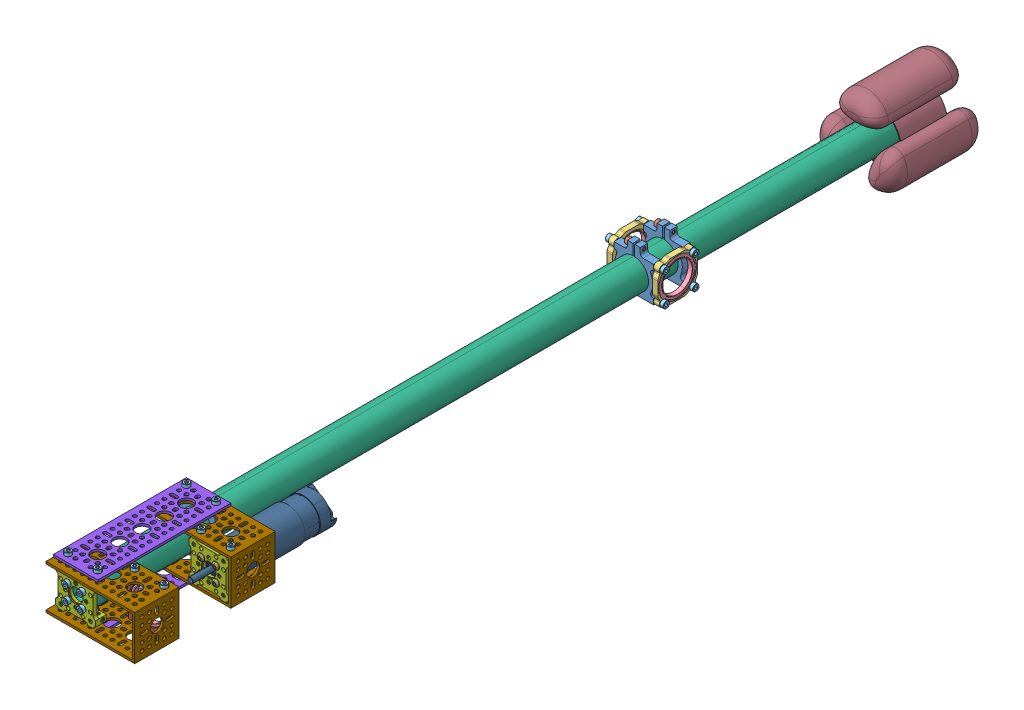
SolidWorks assembly Link2_Assembly, configuration Default. Lengths in mm.
Overall size (120.64 84 949.7).
65 component instances, 13 part files, 73 mates.
Components (placement in the parent):
- 1401-0043-0032 assembly-1: 1401-0043-0032 assembly [Default] at (-0.7931 -4.4026 -28.12) x (1 0 0) z (0 -1 0) size (43.01 8.04 47.02)
  - 1401-0043-0032 assembly.STEP-1: 1401-0043-0032 assembly.STEP [Default] at origin size (43.01 8.04 47.02)
    - 1401-0043-0032.STEP-1: 1401-0043-0032.STEP [Default] at (0.7931 12.12 -4.4026) size (43.01 8 46.5)
    - 2800-0004-0014_90128A207.STEP-1: 2800-0004-0014_90128A207.STEP [Default] at (7.7931 12.12 -28.4026) x (0 0.161804 -0.986823) z (1 0 0) size (7 7 18.01)
- 1401-0043-0032 assembly-2: 1401-0043-0032 assembly [Default] at (-0.7931 -4.4026 3.88) x (1 0 0) z (0 -1 0) size (43.01 8.04 47.02)
  - 1401-0043-0032 assembly.STEP-1: 1401-0043-0032 assembly.STEP [Default] at origin size (43.01 8.04 47.02)
    - 1401-0043-0032.STEP-1: 1401-0043-0032.STEP [Default] at (0.7931 12.12 -4.4026) size (43.01 8 46.5)
    - 2800-0004-0014_90128A207.STEP-1: 2800-0004-0014_90128A207.STEP [Default] at (7.7931 12.12 -28.4026) x (0 0.161804 -0.986823) z (1 0 0) size (7 7 18.01)
- 1603-0032-0032 assembly-1: 1603-0032-0032 assembly [Default] at (9.9811 31.4475 6.7305) x (0 1 0) z (0 0 -1) size (55.53 6 55.53)
  - 1603-0032-0032 assembly.STEP-1: 1603-0032-0032 assembly.STEP [Default] at origin size (55.53 6 55.53)
    - 1603-0032-0032.STEP-1: 1603-0032-0032.STEP [Default] at (-31.4475 11.5189 6.7305) size (43 6 43)
    - 1601-0039-00032.STEP-1: 1601-0039-00032.STEP [Default] at (-31.4475 15.0189 6.7305) x (0.473716 0 0.880678) z (-0.880678 0 0.473716) size (41 5 41)
- 1603-0032-0032 assembly-3: 1603-0032-0032 assembly [Default] at (-9.9811 -31.4475 6.7305) x (0 -1 0) z (0 0 -1) size (55.53 6 55.53)
  - 1603-0032-0032 assembly.STEP-1: 1603-0032-0032 assembly.STEP [Default] at origin size (55.53 6 55.53)
    - 1603-0032-0032.STEP-1: 1603-0032-0032.STEP [Default] at (-31.4475 11.5189 6.7305) size (43 6 43)
    - 1601-0039-00032.STEP-1: 1601-0039-00032.STEP [Default] at (-31.4475 15.0189 6.7305) x (0.473716 0 0.880678) z (-0.880678 0 0.473716) size (41 5 41)
- 2800-0004-0010-1: 2800-0004-0010 [Default] at (17.5 16 16) x (0 0 1) z (-1 0 0) size (7 7 14.01)
- 2800-0004-0010-2: 2800-0004-0010 [Default] at (17.5 16 -16) x (0 0 1) z (-1 0 0) size (7 7 14.01)
- 2800-0004-0010-3: 2800-0004-0010 [Default] at (17.5 -16 -16) x (0 0 1) z (-1 0 0) size (7 7 14.01)
- 2800-0004-0010-4: 2800-0004-0010 [Default] at (17.5 -16 16) x (0 0 1) z (-1 0 0) size (7 7 14.01)
- 2800-0004-0010-5: 2800-0004-0010 [Default] at (-17.5 -16 16) x (0 0 1) z (1 0 0) size (7 7 14.01)
- 2800-0004-0010-6: 2800-0004-0010 [Default] at (-17.5 16 16) x (0 0 1) z (1 0 0) size (7 7 14.01)
- 2800-0004-0010-7: 2800-0004-0010 [Default] at (-17.5 16 -16) x (0 0 1) z (1 0 0) size (7 7 14.01)
- 2800-0004-0010-8: 2800-0004-0010 [Default] at (-17.5 -16 -16) x (0 0 1) z (1 0 0) size (7 7 14.01)
- 4103-0032-0912-1: 4103-0032-0912 [Default] at (0 0 -292) x (1 0 0) z (0 -1 0) size (31.95 912 31.95)
- 1201-0043-0002-1: 1201-0043-0002 [Default] at (0 0 624) x (1 0 0) z (0 1 0) size (43.01 12.01 43.01)
- 1401-0043-0032 assembly-3: 1401-0043-0032 assembly [Default] at (4.4026 -0.7931 475.88) x (0 1 0) z (1 0 0) size (43.01 8.04 47.02)
  - 1401-0043-0032 assembly.STEP-1: 1401-0043-0032 assembly.STEP [Default] at origin size (43.01 8.04 47.02)
    - 1401-0043-0032.STEP-1: 1401-0043-0032.STEP [Default] at (0.7931 12.12 -4.4026) size (43.01 8 46.5)
    - 2800-0004-0014_90128A207.STEP-1: 2800-0004-0014_90128A207.STEP [Default] at (7.7931 12.12 -28.4026) x (0 0.161804 -0.986823) z (1 0 0) size (7 7 18.01)
- 1123-0048-0144-2: 1123-0048-0144 [Default] at (-21.5 2.5 480) x (0 -1 0) z (-1 0 0) size (2.5 144 48)
- 1111-0004-0001-2: 1111-0004-0001 [Default] at (-24 -45.5 629.5) x (0 -1 0) z (0 0 1) size (48 96 48)
- 1111-0004-0001-3: 1111-0004-0001 [Default] at (-24 -45.5 525.5) x (0 -1 0) z (0 0 1) size (48 96 48)
- 2800-0004-0010-9: 2800-0004-0010 [Default] at (-8 8 614) x (0.968627 0.248521 0) z (0 0 -1) size (7 7 14.01)
- 2800-0004-0010-10: 2800-0004-0010 [Default] at (-8 -8 614) x (-0.923728 -0.383049 0) z (0 0 -1) size (7 7 14.01)
- 2800-0004-0010-11: 2800-0004-0010 [Default] at (8 8 614) x (-0.923728 -0.383049 0) z (0 0 -1) size (7 7 14.01)
- 2800-0004-0010-12: 2800-0004-0010 [Default] at (8 -8 614) x (-0.923728 -0.383049 0) z (0 0 -1) size (7 7 14.01)
- 2800-0004-0010-13: 2800-0004-0010 [Default] at (-16 16.5 616) x (0.968627 0 -0.248521) z (0 -1 0) size (7 7 14.01)
- 2800-0004-0010-14: 2800-0004-0010 [Default] at (-16 16.5 488) x (0.968627 0 -0.248521) z (0 -1 0) size (7 7 14.01)
- 2800-0004-0010-15: 2800-0004-0010 [Default] at (16 16.5 616) x (0.968627 0 -0.248521) z (0 -1 0) size (7 7 14.01)
- 2800-0004-0010-16: 2800-0004-0010 [Default] at (16 16.5 488) x (0.968627 0 -0.248521) z (0 -1 0) size (7 7 14.01)
- 2800-0004-0010-17: 2800-0004-0010 [Default] at (-16 -16.5 616) x (0.968627 0 -0.248521) z (0 1 0) size (7 7 14.01)
- 2800-0004-0010-18: 2800-0004-0010 [Default] at (16 -16.5 616) x (0.968627 0 -0.248521) z (0 1 0) size (7 7 14.01)
- 2800-0004-0010-19: 2800-0004-0010 [Default] at (-16 -16.5 488) x (0.968627 0 -0.248521) z (0 1 0) size (7 7 14.01)
- 2800-0004-0010-20: 2800-0004-0010 [Default] at (16 -16.5 488) x (0.968627 0 -0.248521) z (0 1 0) size (7 7 14.01)
- 1123-0048-0144-3: 1123-0048-0144 [Default] at (-21.5 -48 480) x (0 -1 0) z (-1 0 0) size (2.5 144 48)
- 1201-0043-0002-2: 1201-0043-0002 [Default] at (48 0 528) x (1 0 0) z (0 1 0) size (43.01 12.01 43.01)
- 5202-0002-0027 part-1: 5202-0002-0027 part [Default] at (48 0 524) size (37.5 37.5 140.7)
- 2800-0004-0010-21: 2800-0004-0010 [Default] at (64 14 520) x (0.968627 0 -0.248521) z (0 -1 0) size (7 7 14.01)
- 2800-0004-0010-22: 2800-0004-0010 [Default] at (32 14 520) x (0.968627 0 -0.248521) z (0 -1 0) size (7 7 14.01)
- 2800-0004-0010-23: 2800-0004-0010 [Default] at (32 -14 520) x (0.968627 0 -0.248521) z (0 1 0) size (7 7 14.01)
- 2800-0004-0010-24: 2800-0004-0010 [Default] at (64 -14 520) x (0.968627 0 -0.248521) z (0 1 0) size (7 7 14.01)
- 1604-0043-0032 assembly-1: 1604-0043-0032 assembly [Default] at (25.231 4.255 568.0521) x (-1 0 0) z (0 1 0) size (56.75 7 56.75)
  - 1604-0043-0032 assembly.STEP-1: 1604-0043-0032 assembly.STEP [Default] at origin size (56.75 7 56.75)
    - 1604-0043-0032.STEP-1: 1604-0043-0032.STEP [Default] at (-22.769 20.4479 -4.255) size (43 7 43.01)
    - 1601-0039-00032.STEP-1: 1601-0039-00032.STEP [Default] at (-22.769 22.9479 -4.255) x (-0.837169 0 -0.546944) z (-0.546944 0 0.837169) size (41 5 41)
- 2802-0004-0008-1: 2802-0004-0008 [Default] at (56 8 530.2) size (7.6 7.6 10.21)
- 2802-0004-0008-2: 2802-0004-0008 [Default] at (40 8 530.2) size (7.6 7.6 10.21)
- 2800-0004-0010-25: 2800-0004-0010 [Default] at (32 14 592) x (0.968627 0 -0.248521) z (0 -1 0) size (7 7 14.01)
- 2800-0004-0010-26: 2800-0004-0010 [Default] at (64 14 592) x (0.968627 0 -0.248521) z (0 -1 0) size (7 7 14.01)
- 2800-0004-0010-27: 2800-0004-0010 [Default] at (64 -14 592) x (0.968627 0 -0.248521) z (0 1 0) size (7 7 14.01)
- 2800-0004-0010-28: 2800-0004-0010 [Default] at (32 -14 592) x (0.968627 0 -0.248521) z (0 1 0) size (7 7 14.01)
- 2802-0004-0008-3: 2802-0004-0008 [Default] at (56 -8 530.2) size (7.6 7.6 10.21)
- 2802-0004-0008-4: 2802-0004-0008 [Default] at (40 -8 530.2) size (7.6 7.6 10.21)
- Counter_Weight-1: Counter_Weight [Default] at (0 0 -267) size (88.52 84 101.4)
Mates (geometry in assembly coordinates):
- Symmetric2: symmetric aligned: plane of 1401-0043-0032 assembly-1/1401-0043-0032 assembly.STEP-1/1401-0043-0032.STEP-1 through (-21.5 -21.5 -12) normal (-1 0 0); plane of 1401-0043-0032 assembly-1/1401-0043-0032 assembly.STEP-1/1401-0043-0032.STEP-1 through (21.5 -21.5 -12) normal (1 0 0)
- Symmetric1: symmetric aligned: plane of 1401-0043-0032 assembly-1/1401-0043-0032 assembly.STEP-1/1401-0043-0032.STEP-1 through (-20.5 19 -16) normal (0 1 0); plane of 1401-0043-0032 assembly-1/1401-0043-0032 assembly.STEP-1/1401-0043-0032.STEP-1 through (-20.5 -19 -16) normal (0 -1 0); plane of assembly through (0 0 0) normal (0 1 0)
- Distance1: distance = 12 mm: plane of assembly through (0 0 0) normal (0 0 1); plane of assembly; plane of 1401-0043-0032 assembly-1/1401-0043-0032 assembly.STEP-1/1401-0043-0032.STEP-1 through (0 0 -12) normal (0 0 1)
- Concentric1: concentric aligned: cylinder of 1401-0043-0032 assembly-1/1401-0043-0032 assembly.STEP-1/1401-0043-0032.STEP-1 through (0 0 -20) axis (0 0 1) radius 16; cylinder of 1401-0043-0032 assembly-2/1401-0043-0032 assembly.STEP-1/1401-0043-0032.STEP-1 through (0 0 12) axis (0 0 1) radius 16
- Distance2: distance = 12 mm: plane of assembly through (0 0 0) normal (0 0 1); plane of assembly; plane of 1401-0043-0032 assembly-2/1401-0043-0032 assembly.STEP-1/1401-0043-0032.STEP-1 through (0 0 12) normal (0 0 -1)
- Coincident6: coincident anti-aligned: plane of 1401-0043-0032 assembly-2/1401-0043-0032 assembly.STEP-1/1401-0043-0032.STEP-1 through (21.5 -21.5 20) normal (1 0 0); plane of 1603-0032-0032 assembly-1/1603-0032-0032 assembly.STEP-1/1603-0032-0032.STEP-1 through (21.5 0 0) normal (-1 0 0)
- Concentric5: concentric anti-aligned: circle of 1401-0043-0032 assembly-1/1401-0043-0032 assembly.STEP-1/1401-0043-0032.STEP-1; cylinder of 1603-0032-0032 assembly-1/1603-0032-0032 assembly.STEP-1/1603-0032-0032.STEP-1 through (24.5 16 -16) axis (1 0 0) radius 2
- Parallel1: parallel aligned: plane of 1603-0032-0032 assembly-1/1603-0032-0032 assembly.STEP-1/1603-0032-0032.STEP-1 through (85.3112 21.5 21.5) normal (0 1 0)
- Coincident11: coincident aligned: plane of 2800-0004-0010-3 through (27.5 -16 -16) normal (-1 0 0); plane of 2800-0004-0010-4 through (27.5 -16 16) normal (-1 0 0)
- Coincident12: coincident aligned: plane of 2800-0004-0010-2 through (27.5 16 -16) normal (-1 0 0); plane of 2800-0004-0010-3 through (27.5 -16 -16) normal (-1 0 0)
- Coincident13: coincident aligned: plane of 2800-0004-0010-1 through (27.5 16 16) normal (-1 0 0); plane of 2800-0004-0010-2 through (27.5 16 -16) normal (-1 0 0)
- Coincident14: coincident anti-aligned: plane of 1603-0032-0032 assembly-1/1603-0032-0032 assembly.STEP-1/1603-0032-0032.STEP-1 through (27.5 0 0) normal (1 0 0); plane of 2800-0004-0010-1 through (27.5 16 16) normal (-1 0 0)
- Concentric8: concentric anti-aligned: cylinder of 1603-0032-0032 assembly-1/1603-0032-0032 assembly.STEP-1/1603-0032-0032.STEP-1 through (24.5 16 16) axis (1 0 0) radius 2; cylinder of 2800-0004-0010-1 through (31.5 16 16) axis (-1 0 0) radius 3.5
- Concentric9: concentric anti-aligned: cylinder of 1603-0032-0032 assembly-1/1603-0032-0032 assembly.STEP-1/1603-0032-0032.STEP-1 through (24.5 16 -16) axis (1 0 0) radius 2; cylinder of 2800-0004-0010-2 through (31.5 16 -16) axis (-1 0 0) radius 3.5
- Concentric10: concentric anti-aligned: cylinder of 1603-0032-0032 assembly-1/1603-0032-0032 assembly.STEP-1/1603-0032-0032.STEP-1 through (24.5 -16 -16) axis (1 0 0) radius 2; cylinder of 2800-0004-0010-3 through (31.5 -16 -16) axis (-1 0 0) radius 3.5
- Concentric11: concentric anti-aligned: cylinder of 1603-0032-0032 assembly-1/1603-0032-0032 assembly.STEP-1/1603-0032-0032.STEP-1 through (24.5 -16 16) axis (1 0 0) radius 2; cylinder of 2800-0004-0010-4 through (31.5 -16 16) axis (-1 0 0) radius 3.5
- Concentric13: concentric anti-aligned: cylinder of 1401-0043-0032 assembly-2/1401-0043-0032 assembly.STEP-1/1401-0043-0032.STEP-1 through (0 0 12) axis (0 0 1) radius 16; cylinder of 4103-0032-0912-1 through (0 0 620) axis (0 0 -1) radius 15.975
- Distance4: distance = 600 mm aligned: plane of 1401-0043-0032 assembly-2/1401-0043-0032 assembly.STEP-1/1401-0043-0032.STEP-1 through (0 0 20) normal (0 0 1); plane of 4103-0032-0912-1 through (0 0 620) normal (0 0 1)
- Coincident18: coincident anti-aligned: plane of 4103-0032-0912-1 through (0 0 -292) normal (0 -1 0)
- Concentric14: concentric aligned: cylinder of 4103-0032-0912-1 through (-8 8 620) axis (0 0 -1) radius 2.7; cylinder of 1201-0043-0002-1 through (-8 8 624) axis (0 0 -1) radius 2
- Concentric15: concentric aligned: cylinder of 4103-0032-0912-1 through (8 8 620) axis (0 0 -1) radius 2.7; cylinder of 1201-0043-0002-1 through (8 8 624) axis (0 0 -1) radius 2
- Coincident19: coincident anti-aligned: plane of 4103-0032-0912-1 through (0 0 620) normal (0 0 1); plane of 1201-0043-0002-1 through (0 0 620) normal (0 0 -1)
- Concentric16: concentric anti-aligned: cylinder of 4103-0032-0912-1 through (0 0 620) axis (0 0 -1) radius 15.975; cylinder of 1401-0043-0032 assembly-3/1401-0043-0032 assembly.STEP-1/1401-0043-0032.STEP-1 through (0 0 484) axis (0 0 1) radius 16
- Parallel3: parallel aligned: plane of 1201-0043-0002-1 through (0 21.5 633.1924) normal (0 1 0); plane of 1401-0043-0032 assembly-3/1401-0043-0032 assembly.STEP-1/1401-0043-0032.STEP-1 through (21.5 21.5 492) normal (0 1 0)
- Coincident30: coincident anti-aligned: plane of 1201-0043-0002-1 through (0 21.5 633.1924) normal (0 1 0); plane of 1111-0004-0001-2 through (-24 21.5 629.5) normal (0 -1 0)
- Coincident33: coincident aligned: plane of 1111-0004-0001-2 through (72 -45.5 629.5) normal (1 0 0); plane of 1111-0004-0001-3 through (72 -45.5 525.5) normal (1 0 0)
- Coincident34: coincident aligned: plane of 1111-0004-0001-2 through (-24 24 629.5) normal (0 1 0); plane of 1111-0004-0001-3 through (-24 24 525.5) normal (0 1 0)
- Concentric19: concentric aligned: circle of 1401-0043-0032 assembly-3/1401-0043-0032 assembly.STEP-1/1401-0043-0032.STEP-1; cylinder of 1111-0004-0001-3 through (-16 31.5 488) axis (0 -1 0) radius 2
- Coincident36: coincident anti-aligned: plane of 1123-0048-0144-2 through (-21.5 24 624) normal (0 -1 0); plane of 1111-0004-0001-2 through (-24 24 629.5) normal (0 1 0)
- Parallel4: parallel aligned: plane of 1201-0043-0002-1 through (0 0 624) normal (0 0 1); plane of 1111-0004-0001-2 through (72 -69.5 632) normal (0 0 1)
- Concentric20: concentric aligned: circle of 1201-0043-0002-1; cylinder of 1111-0004-0001-2 through (-16 31.5 616) axis (0 -1 0) radius 2
- Concentric21: concentric anti-aligned: cylinder of 1123-0048-0144-2 through (-16 16.5 616) axis (0 1 0) radius 2; cylinder of 1111-0004-0001-2 through (-16 31.5 616) axis (0 -1 0) radius 2
- Concentric22: concentric anti-aligned: cylinder of 1123-0048-0144-2 through (16 16.5 616) axis (0 1 0) radius 2; cylinder of 1111-0004-0001-2 through (16 31.5 616) axis (0 -1 0) radius 2
- Concentric23: concentric anti-aligned: cylinder of 1123-0048-0144-2 through (-16 16.5 488) axis (0 1 0) radius 2; cylinder of 1111-0004-0001-3 through (-16 31.5 488) axis (0 -1 0) radius 2
- Coincident37: coincident aligned: plane of 2800-0004-0010-9 through (-8 8 624) normal (0 0 -1); plane of 2800-0004-0010-10 through (-8 -8 624) normal (0 0 -1)
- Coincident38: coincident aligned: plane of 2800-0004-0010-10 through (-8 -8 624) normal (0 0 -1); plane of 2800-0004-0010-11 through (8 8 624) normal (0 0 -1)
- Coincident39: coincident aligned: plane of 2800-0004-0010-10 through (-8 -8 624) normal (0 0 -1); plane of 2800-0004-0010-12 through (8 -8 624) normal (0 0 -1)
- Coincident40: coincident anti-aligned: plane of 1201-0043-0002-1 through (0 0 624) normal (0 0 1); plane of 2800-0004-0010-9 through (-8 8 624) normal (0 0 -1)
- Concentric24: concentric aligned: cylinder of 1201-0043-0002-1 through (-8 8 624) axis (0 0 -1) radius 2; cylinder of 2800-0004-0010-9 through (-8 8 628) axis (0 0 -1) radius 3.5
- Concentric25: concentric aligned: cylinder of 1201-0043-0002-1 through (8 8 624) axis (0 0 -1) radius 2; cylinder of 2800-0004-0010-11 through (8 8 628) axis (0 0 -1) radius 3.5
- Concentric26: concentric aligned: cylinder of 1201-0043-0002-1 through (8 -8 624) axis (0 0 -1) radius 2; cylinder of 2800-0004-0010-12 through (8 -8 628) axis (0 0 -1) radius 3.5
- Concentric27: concentric aligned: cylinder of 1201-0043-0002-1 through (-8 -8 624) axis (0 0 -1) radius 2; cylinder of 2800-0004-0010-10 through (-8 -8 628) axis (0 0 -1) radius 3.5
- Coincident41: coincident aligned: plane of 2800-0004-0010-14 through (-16 30.5 488) normal (0 1 0); plane of 2800-0004-0010-15 through (16 30.5 616) normal (0 1 0)
- Coincident42: coincident aligned: plane of 2800-0004-0010-13 through (-16 30.5 616) normal (0 1 0); plane of 2800-0004-0010-15 through (16 30.5 616) normal (0 1 0)
- Coincident43: coincident aligned: plane of 2800-0004-0010-13 through (-16 30.5 616) normal (0 1 0); plane of 2800-0004-0010-16 through (16 30.5 488) normal (0 1 0)
- Coincident44: coincident anti-aligned: plane of 1123-0048-0144-2 through (24 26.5 624) normal (0 1 0); plane of 2800-0004-0010-13 through (-16 26.5 616) normal (0 -1 0)
- Concentric29: concentric anti-aligned: cylinder of 1123-0048-0144-2 through (-16 16.5 616) axis (0 1 0) radius 2; cylinder of 2800-0004-0010-13 through (-16 30.5 616) axis (0 -1 0) radius 3.5
- Concentric30: concentric anti-aligned: cylinder of 1123-0048-0144-2 through (16 16.5 616) axis (0 1 0) radius 2; cylinder of 2800-0004-0010-15 through (16 30.5 616) axis (0 -1 0) radius 3.5
- Concentric31: concentric anti-aligned: cylinder of 1123-0048-0144-2 through (-16 16.5 488) axis (0 1 0) radius 2; cylinder of 2800-0004-0010-14 through (-16 30.5 488) axis (0 -1 0) radius 3.5
- Concentric32: concentric anti-aligned: cylinder of 1123-0048-0144-2 through (16 16.5 488) axis (0 1 0) radius 2; cylinder of 2800-0004-0010-16 through (16 30.5 488) axis (0 -1 0) radius 3.5
- Coincident45: coincident anti-aligned: plane of 1111-0004-0001-3 through (-24 21.5 525.5) normal (0 -1 0); plane of 1201-0043-0002-2 through (48 21.5 537.1924) normal (0 1 0)
- Coincident46: coincident anti-aligned: plane of 1111-0004-0001-3 through (69.5 21.5 528) normal (-1 0 0); plane of 1201-0043-0002-2 through (69.5 0 524) normal (1 0 0)
- Coincident47: coincident aligned: cylinder of 1111-0004-0001-3 through (64 31.5 520) axis (0 -1 0) radius 2; circle of 1201-0043-0002-2
- Concentric33: concentric aligned: cylinder of 1201-0043-0002-2 through (48 0 528) axis (0 0 -1) radius 7; cylinder of 5202-0002-0027 part-1 through (48 0 520.95) axis (0 0 -1) radius 16
- Coincident48: coincident anti-aligned: plane of 1201-0043-0002-2 through (48 0 524) normal (0 0 -1); plane of 5202-0002-0027 part-1 through (48 0 524) normal (0 0 1)
- Coincident49: coincident aligned: cylinder of 1201-0043-0002-2 through (40 8 528) axis (0 0 -1) radius 2; circle of 5202-0002-0027 part-1
- Coincident50: coincident aligned: plane of 2800-0004-0010-21 through (64 28 520) normal (0 1 0); plane of 2800-0004-0010-22 through (32 28 520) normal (0 1 0)
- Coincident51: coincident anti-aligned: plane of 1111-0004-0001-3 through (-24 24 525.5) normal (0 1 0); plane of 2800-0004-0010-22 through (32 24 520) normal (0 -1 0)
- Concentric34: concentric aligned: cylinder of 1111-0004-0001-3 through (32 31.5 520) axis (0 -1 0) radius 2; cylinder of 2800-0004-0010-22 through (32 28 520) axis (0 -1 0) radius 3.5
- Concentric35: concentric aligned: cylinder of 1111-0004-0001-3 through (64 31.5 520) axis (0 -1 0) radius 2; cylinder of 2800-0004-0010-21 through (64 28 520) axis (0 -1 0) radius 3.5
- Coincident52: coincident aligned: plane of 2802-0004-0008-1 through (56 6 530.2) normal (0 0 1); plane of 2802-0004-0008-2 through (40 6 530.2) normal (0 0 1)
- Coincident53: coincident anti-aligned: plane of 1201-0043-0002-2 through (48 0 528) normal (0 0 1); plane of 2802-0004-0008-1 through (56 4.2 528) normal (0 0 -1)
- Concentric36: concentric anti-aligned: cylinder of 1201-0043-0002-2 through (56 8 528) axis (0 0 -1) radius 2; cylinder of 2802-0004-0008-1 through (56 8 530.2) axis (0 0 1) radius 3.8
- Concentric37: concentric anti-aligned: cylinder of 1201-0043-0002-2 through (40 8 528) axis (0 0 -1) radius 2; cylinder of 2802-0004-0008-2 through (40 8 530.2) axis (0 0 1) radius 3.8
- Concentric38: concentric aligned: cylinder of 5202-0002-0027 part-1 through (48 0 442.6) axis (0 0 1) radius 18.75; cylinder of 1604-0043-0032 assembly-1/1604-0043-0032 assembly.STEP-1/1601-0039-00032.STEP-1 through (48 0 588.5) axis (0 0 1) radius 16
- Coincident54: coincident aligned: cylinder of 1111-0004-0001-2 through (64 31.5 592) axis (0 -1 0) radius 2; circle of 1604-0043-0032 assembly-1/1604-0043-0032 assembly.STEP-1/1604-0043-0032.STEP-1
- Coincident55: coincident aligned: plane of 2800-0004-0010-25 through (32 28 592) normal (0 1 0); plane of 2800-0004-0010-26 through (64 28 592) normal (0 1 0)
- Coincident56: coincident anti-aligned: plane of 1111-0004-0001-2 through (-24 24 629.5) normal (0 1 0); plane of 2800-0004-0010-26 through (64 24 592) normal (0 -1 0)
- Concentric39: concentric aligned: cylinder of 1111-0004-0001-2 through (64 31.5 592) axis (0 -1 0) radius 2; cylinder of 2800-0004-0010-26 through (64 28 592) axis (0 -1 0) radius 3.5
- Concentric40: concentric aligned: cylinder of 1111-0004-0001-2 through (32 31.5 592) axis (0 -1 0) radius 2; cylinder of 2800-0004-0010-25 through (32 28 592) axis (0 -1 0) radius 3.5
- Concentric41: concentric anti-aligned: circle of Counter_Weight-1; cylinder of 4103-0032-0912-1 through (0 0 620) axis (0 0 -1) radius 15.975
- Coincident57: coincident aligned: plane of 4103-0032-0912-1 through (0 0 -292) normal (0 0 -1); plane of Counter_Weight-1 through (0 0 -292) normal (0 0 -1)
- Coincident58: coincident aligned: plane of Counter_Weight-1 through (0 0 -267) normal (1 0 0)
